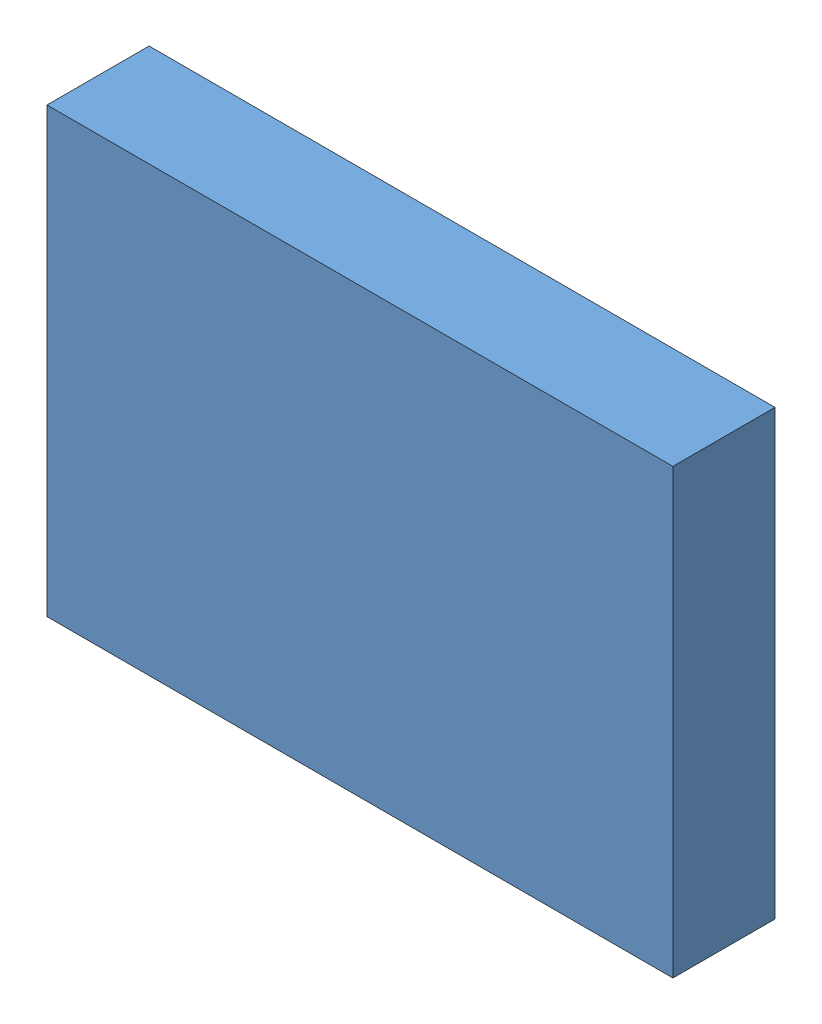
SolidWorks assembly Ensamblaje4, configuration Predeterminado. Lengths in mm.
Overall size (183.83 164.33 32.13).
2 component instances, 2 part files, 0 mates.
Components (placement in the parent):
- cajon^Ensamblaje4-1: cajon^Ensamblaje4 [Predeterminado] at origin size (183.83 130.13 30) (virtual)
- Simulacion Riego Automatico-2: Simulacion Riego Automatico [Predeterminado] at (11.4124 -88.5895 7.0667) size (155 105 28.62)
